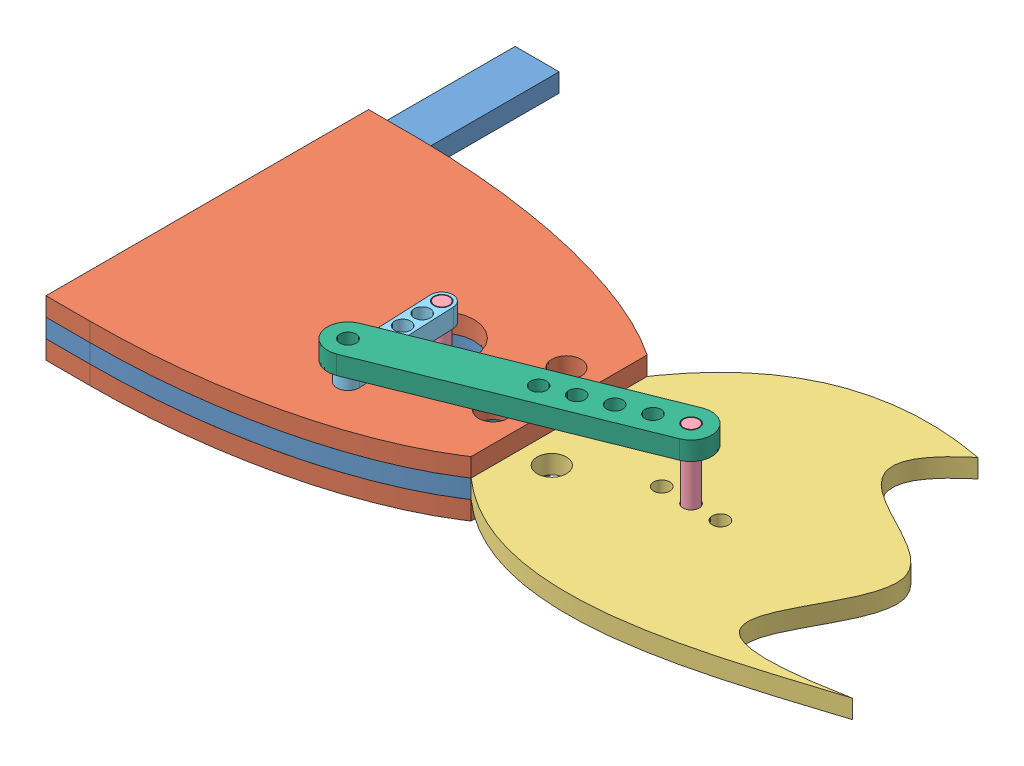
SolidWorks assembly Fish assambly, configuration Default. Lengths in mm.
Overall size (250 36.35 160).
8 component instances, 6 part files, 18 mates.
Components (placement in the parent):
- Rear body-1: Rear body [Default] at (1.7287 59.4608 169.7465) size (120 6.35 160)
- Rear body flank-1: Rear body flank [Default] at (1.7287 65.8108 169.7465) size (120 6.35 110)
- Rear body flank-2: Rear body flank [Default] at (1.7287 53.1108 169.7465) size (120 6.35 110)
- Tail Flank-1: Tail Flank [Default] at (50.3368 59.4608 192.8979) size (130 6.35 119.84)
- peg-1: peg [Default] at (66.7287 53.1108 114.7465) size (5 30 5)
- peg-2: peg [Default] at (151.7287 59.4608 114.7465) x (0.974657 0 -0.223704) z (0.223704 0 0.974657) size (5 30 5)
- Rockerarm-1: Rockerarm [Default] at (68.1831 76.7608 148.2149) x (0.999057 0 -0.043415) z (0.043415 0 0.999057) size (7.5 6.35 41)
- perp arm-1: perp arm [Default] at (68.1831 83.1108 148.2149) x (0.371871 0 0.928284) z (-0.928284 0 0.371871) size (14 6.35 104)
Mates (geometry in assembly coordinates):
- Coincident2: coincident anti-aligned: plane of Rear body-1 through (1.7287 65.8108 114.7465) normal (0 1 0); plane of Rear body flank-1 through (1.7287 65.8108 114.7465) normal (0 -1 0)
- Coincident3: coincident aligned: plane of Rear body-1 through (106.7287 65.8108 84.7465) normal (1 0 0); plane of Rear body flank-1 through (106.7287 72.1608 84.7465) normal (1 0 0)
- Coincident4: coincident aligned: plane of Rear body-1 through (-13.2713 65.8108 169.7465) normal (0 0 1); plane of Rear body flank-1 through (-13.2713 72.1608 169.7465) normal (0 0 1)
- Coincident5: coincident anti-aligned: plane of Rear body-1 through (1.7287 59.4608 114.7465) normal (0 -1 0); plane of Rear body flank-2 through (1.7287 59.4608 114.7465) normal (0 1 0)
- Coincident6: coincident aligned: plane of Rear body-1 through (106.7287 65.8108 84.7465) normal (1 0 0); plane of Rear body flank-2 through (106.7287 59.4608 84.7465) normal (1 0 0)
- Coincident7: coincident aligned: plane of Rear body-1 through (-13.2713 65.8108 169.7465) normal (0 0 1); plane of Rear body flank-2 through (-13.2713 59.4608 169.7465) normal (0 0 1)
- Coincident8: coincident anti-aligned: plane of Rear body-1 through (106.7287 65.8108 84.7465) normal (1 0 0); plane of Tail Flank-1 through (106.7287 65.8108 84.7465) normal (-1 0 0)
- Coincident9: coincident anti-aligned: line of Rear body-1 through (106.7287 65.8108 144.7465) axis (0 0 -1); line of Tail Flank-1 through (106.7287 65.8108 84.7465) axis (0 0 1)
- Coincident10: coincident: point of Rear body-1; line of Tail Flank-1 through (106.7287 65.8108 84.7465) axis (0 -1 0)
- Coincident12: coincident anti-aligned: circle of Rear body flank-2; plane of peg-1 through (66.7287 53.1108 114.7465) normal (0 -1 0)
- Concentric1: concentric aligned: cylinder of Rear body-1 through (66.7287 65.8108 114.7465) axis (0 -1 0) radius 11; cylinder of peg-1 through (66.7287 83.1108 114.7465) axis (0 -1 0) radius 2.5
- Coincident13: coincident aligned: plane of Tail Flank-1 through (141.1532 59.4608 55.422) normal (0 -1 0); plane of peg-2 through (151.7287 59.4608 114.7465) normal (0 -1 0)
- Concentric2: concentric aligned: cylinder of Tail Flank-1 through (151.7287 65.8108 114.7465) axis (0 -1 0) radius 2.75; cylinder of peg-2 through (151.7287 89.4608 114.7465) axis (0 -1 0) radius 2.5
- Coincident14: coincident aligned: plane of peg-1 through (66.7287 83.1108 114.7465) normal (0 1 0); plane of Rockerarm-1 through (66.7287 83.1108 114.7465) normal (0 1 0)
- Concentric3: concentric aligned: cylinder of peg-1 through (66.7287 83.1108 114.7465) axis (0 -1 0) radius 2.5; cylinder of Rockerarm-1 through (66.7287 83.1108 114.7465) axis (0 -1 0) radius 2.75
- Coincident15: coincident aligned: plane of peg-2 through (151.7287 89.4608 114.7465) normal (0 1 0); plane of perp arm-1 through (151.7287 89.4608 114.7465) normal (0 1 0)
- Concentric4: concentric aligned: cylinder of peg-2 through (151.7287 89.4608 114.7465) axis (0 -1 0) radius 2.5; cylinder of perp arm-1 through (151.7287 89.4608 114.7465) axis (0 -1 0) radius 2.75
- Concentric5: concentric anti-aligned: circle of Rockerarm-1; cylinder of perp arm-1 through (68.1831 89.4608 148.2149) axis (0 -1 0) radius 2.75
